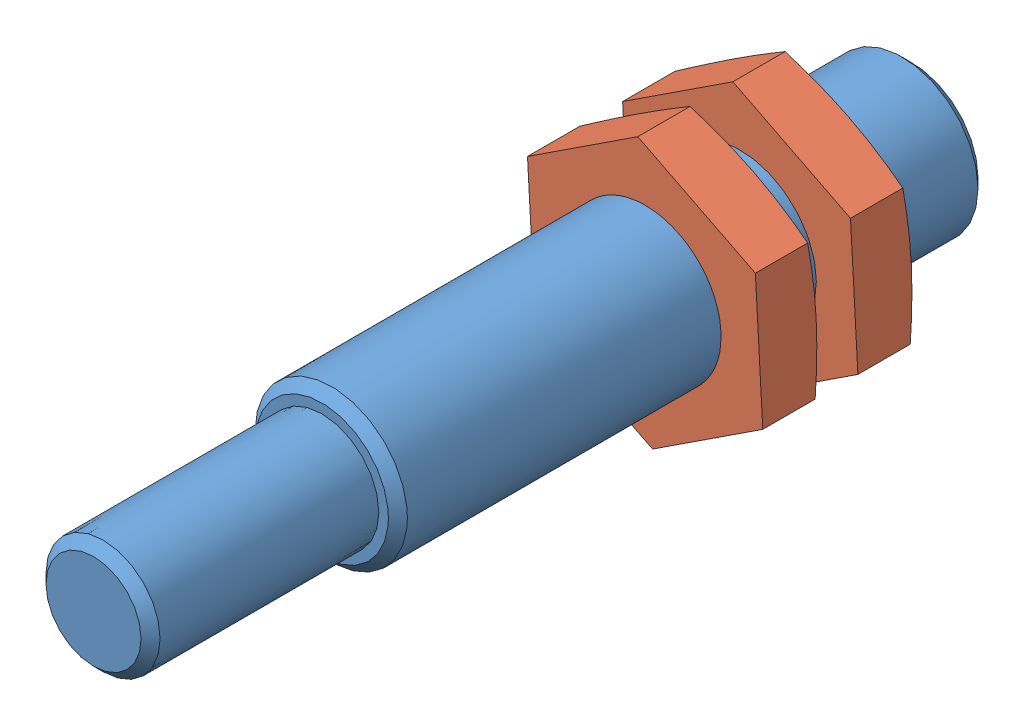
SolidWorks assembly A55, configuration 默认. Lengths in mm.
Overall size (18.17 17.63 43).
3 component instances, 2 part files, 5 mates.
Components (placement in the parent):
- A55-1-1: A55-1 [默认] at (-4.0245 1.4173 -30) size (8 8 43)
- small hex thin nuts-fine pitch thread gb-1: small hex thin nuts-fine pitch thread gb [GB_FASTENER_NUT_SSFNTT M8X1.0-N] at (-4.0245 1.4173 -21) x (0.83657 0.54786 0) z (0 0 1) size (13.86 12 3)
- small hex thin nuts-fine pitch thread gb-2: small hex thin nuts-fine pitch thread gb [GB_FASTENER_NUT_SSFNTT M8X1.0-N] at (-4.0245 1.4173 -16) x (0.83657 0.54786 0) z (0 0 1) size (13.86 12 3)
Mates (geometry in assembly coordinates):
- 同心1: concentric aligned: cylinder of A55-1-1 through (-4.0245 1.4173 -20) axis (0 0 -1) radius 4; circle of ?
- 重合3: coincident aligned: plane of A55-2-1 through (2.1606 -1.7042 -24) normal (0.998421 0.056175 0); plane of A55-2-2 through (2.1606 -1.7042 -19) normal (0.998421 0.056175 0)
- 同心2: concentric aligned: cylinder of A55-1-1 through (-4.0245 1.4173 -20) axis (0 0 -1) radius 4; circle of small hex thin nuts-fine pitch thread gb-1
- 距离2: distance = 2 mm anti-aligned: plane of A55-2-2 through (-3.6353 -5.4999 -19) normal (0 0 -1); plane of A55-2-1 through (-3.6353 -5.4999 -21) normal (0 0 1)
- 距离3: distance = 6 mm aligned: plane of A55-2-1 through (-3.6353 -5.4999 -24) normal (0 0 -1); plane of A55-1-1 through (-4.0245 1.4173 -30) normal (0 0 -1)
